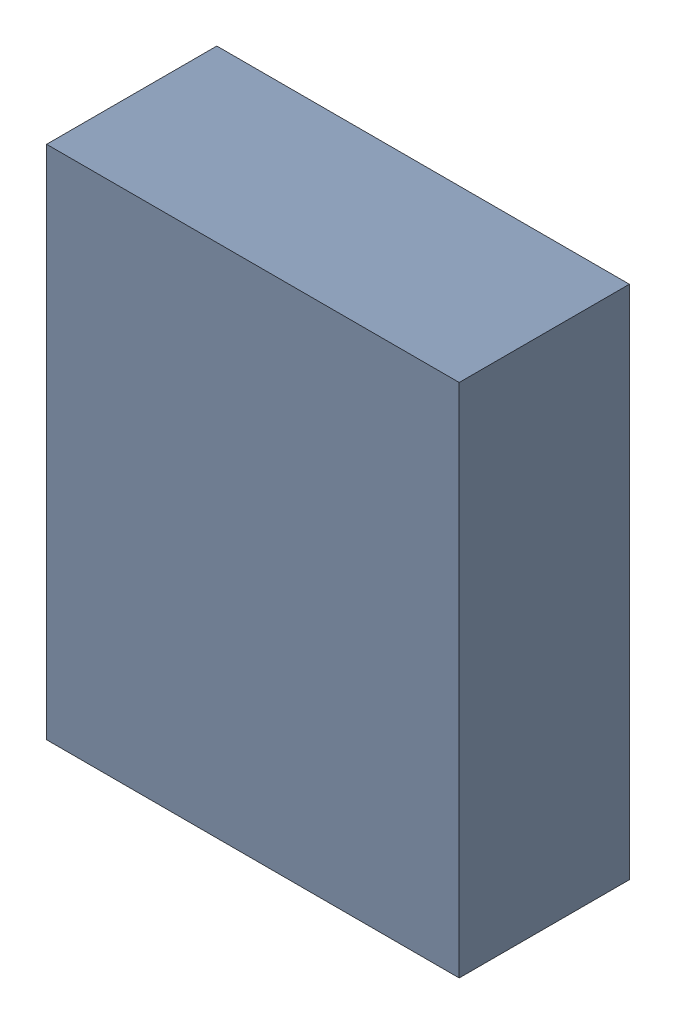
SolidWorks assembly U301_1PCB, configuration Default. Lengths in mm.
Overall size (4 5 1.65).
2 component instances, 1 part files, 0 mates.
Components (placement in the parent):
- 761608904-1: 761608904 [Default] at (150.3 107 0.1) size (4 5 1.65)
  - Extruded_35-1: Extruded_35 [Default] at origin size (4 5 1.65)
